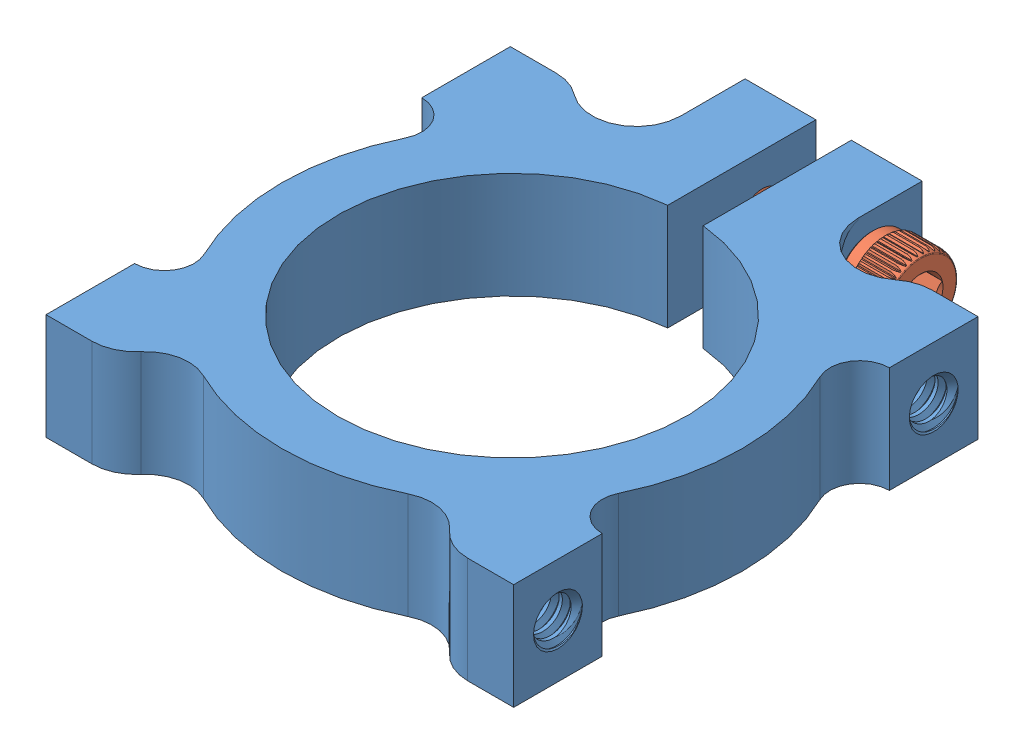
SolidWorks assembly 25m Bore Side Tapped Clamping Mount, configuration Default. Lengths in mm.
Overall size (33.76 7.62 39.7).
2 component instances, 2 part files, 0 mates.
Components (placement in the parent):
- 25m Bore Side Tapped Clamping Mount-1: 25m Bore Side Tapped Clamping Mount [Default] at (0.615 -8.6446 6.1668) size (33.76 7.62 39.7)
- #6-32 0_5 Bolt-1: #6-32 0_5 Bolt [Default] at (-31.135 -4.8346 -13.2719) x (0 0.2706 0.962692) z (-1 0 0) size (5.57 5.57 16.21)
